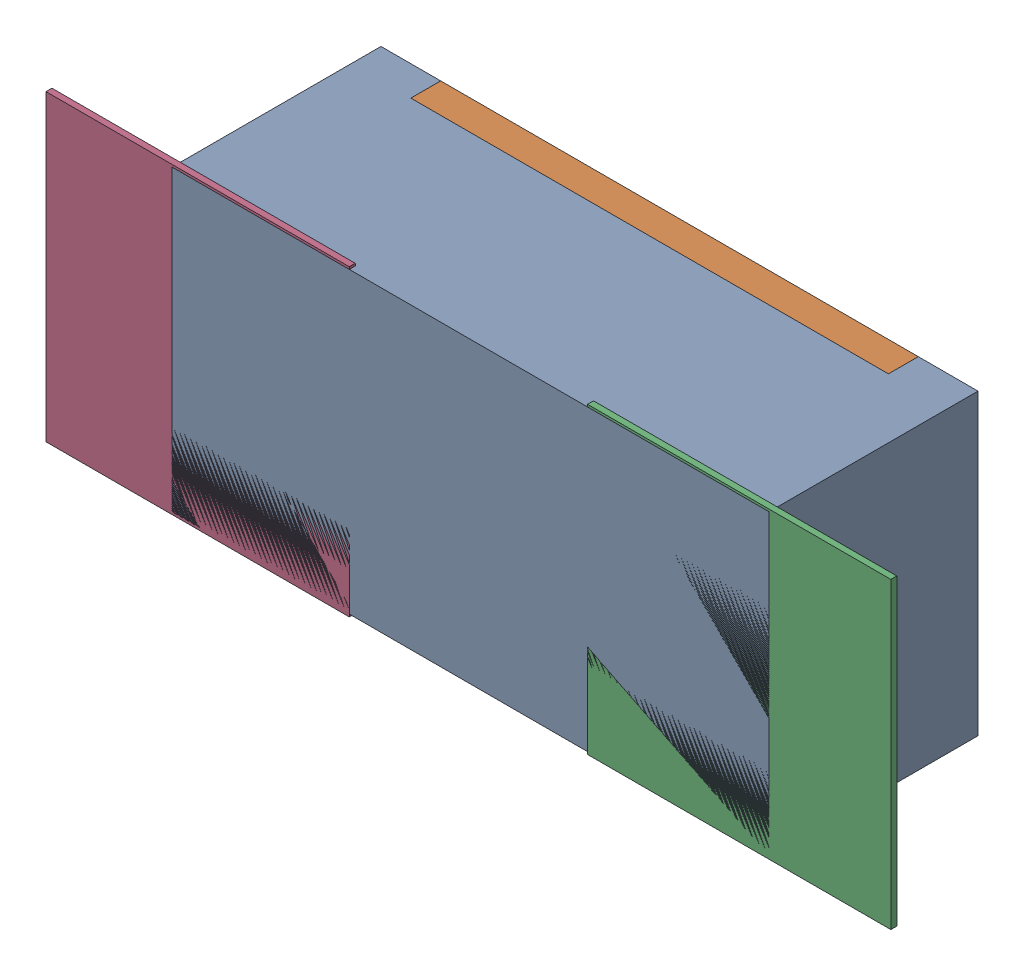
SolidWorks assembly R105, configuration Défaut. Lengths in mm.
Overall size (1.42 0.51 0.35).
5 component instances, 2 part files, 0 mates.
Components (placement in the parent):
- R0402-1: R0402 [Défaut] at (19.1771 -22.9687 -2.0818) x (1 0 0) z (0 0 -1) size (1 0.5 0.35)
- 6504207776-1: 6504207776 [Défaut] at (19.6271 -22.9688 -2.0918) size (0.51 0.51 0.01)
  - Extruded-1: Extruded [Défaut] at origin size (0.51 0.51 0.01)
- 6504207776-2: 6504207776 [Défaut] at (18.72 -22.9688 -2.0918) size (0.51 0.51 0.01)
  - Extruded-1: Extruded [Défaut] at origin size (0.51 0.51 0.01)
